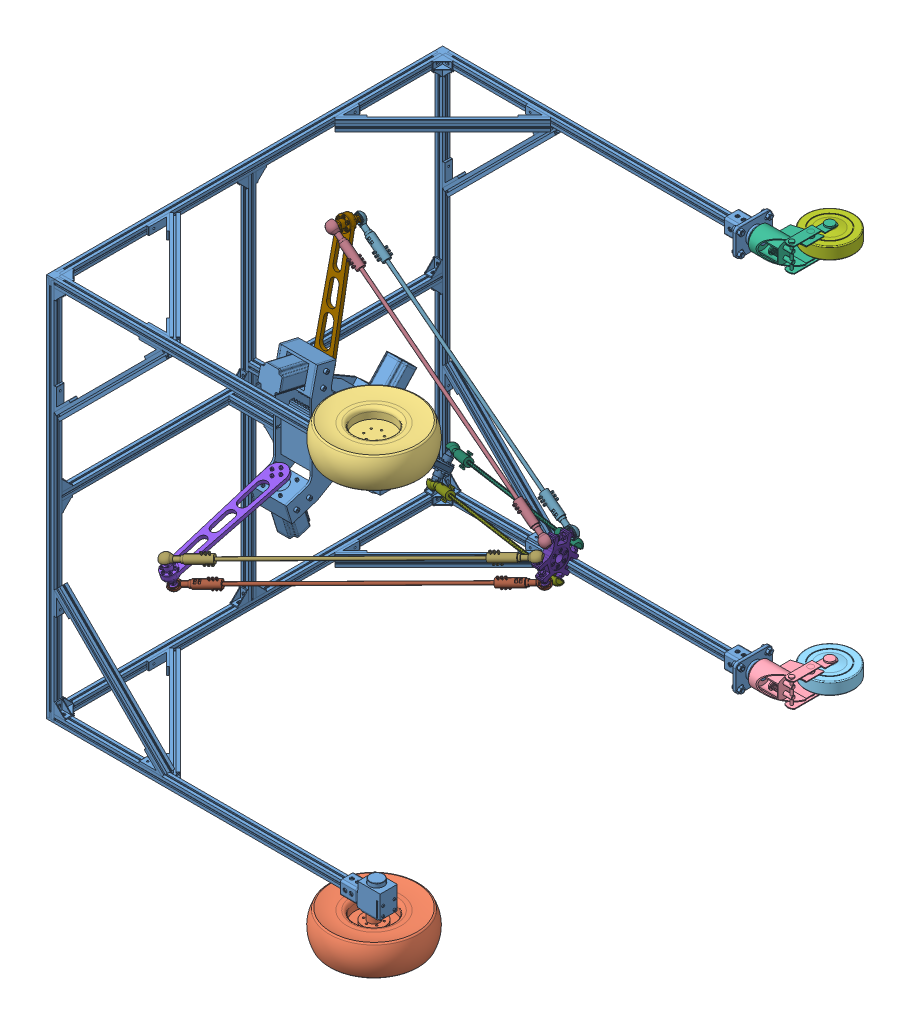
SolidWorks assembly ASM_copy, configuration Default. Lengths in mm.
Overall size (1014.86 1201.01 1337.44).
17 component instances, 17 part files, 27 mates.
Components (placement in the parent):
- Base-1: Base [默认] at (153.8383 -97.0811 -329.752) size (890.6 1072.4 1090.2)
- Driving_Wheel_1-1: Driving_Wheel_1 [默认] at (1013.8593 45.6114 1231.8039) x (1 0 0) z (0 1 0) size (257.62 257.62 86.31)
- Driving_Wheel_2-1: Driving_Wheel_2 [默认] at (1013.8593 1154.0114 1231.6593) x (1 0 0) z (0 -1 0) size (257.62 257.62 86.31)
- Link_Idler_Wheel_1-1: Link_Idler_Wheel_1 [默认] at (928.8665 41.2421 177.5322) x (0 -0.057419 0.99835) z (0 0.99835 0.057419) size (146.07 110.26 71.01)
- Idler_Wheel_1-1: Idler_Wheel_1 [默认] at (1090.3592 104.9114 111.5316) x (0 1 0) z (0.688622 0 -0.72512) size (40 125 125)
- Link_Idler_Wheel_2-1: Link_Idler_Wheel_2 [默认] at (928.8665 1031.2421 177.5322) x (0 -0.057419 0.99835) z (0 0.99835 0.057419) size (146.07 110.26 71.01)
- Idler_Wheel_2-1: Idler_Wheel_2 [默认] at (1090.3592 1094.9114 111.5316) x (0 -1 0) z (-0.118719 0 0.992928) size (40 125 125)
- Driving_Arm_1-1: Driving_Arm_1 [默认] at (491.5187 730.2809 769.1723) x (-0.999786 0.00612 -0.019764) z (-0.02069 -0.295741 0.955044) size (50 94.64 334)
- Driving_Arm_2-1: Driving_Arm_2 [默认] at (491.5187 586.7095 565.8859) x (-0.999786 -0.020176 0.004582) z (-0.02069 0.974963 -0.221403) size (50 94.64 334)
- Driving_Arm_3-1: Driving_Arm_3 [默认] at (491.5187 482.444 791.8655) x (-0.999786 0.014056 0.015182) z (-0.02069 -0.679222 -0.733641) size (50 94.64 334)
- Idler_Arm_1-1: Idler_Arm_1 [默认] at (625.108 556.338 323.4904) x (0.112964 0.846653 0.520017) z (0.510672 -0.498423 0.700563) size (34.32 751.8 29.42)
- Idler_Arm_2-1: Idler_Arm_2 [默认] at (1145.8798 654.078 1263.8018) x (-0.045285 -0.904508 -0.424046) z (-0.521051 0.383554 -0.762491) size (34.32 751.8 29.42)
- Idler_Arm_3-1: Idler_Arm_3 [默认] at (693.4424 1428.9939 737.0931) x (-0.131684 -0.36526 -0.921545) z (-0.506168 -0.774538 0.379322) size (34.32 751.8 29.42)
- Idler_Arm_4-1: Idler_Arm_4 [默认] at (170.3914 517.6998 469.2695) x (0.043969 0.228668 0.972511) z (0.521163 0.82525 -0.217605) size (34.32 751.8 29.42)
- Idler_Arm_5-1: Idler_Arm_5 [默认] at (625.3703 956.5035 862.6088) x (0.111171 -0.872414 0.475956) z (0.511065 -0.360557 -0.780264) size (34.32 751.8 29.42)
- Idler_Arm_6-1: Idler_Arm_6 [默认] at (1153.2971 113.313 445.7946) x (-0.084237 0.852323 -0.516188) z (-0.516187 0.405778 0.754252) size (34.32 751.8 29.42)
- End_Platform-1: End_Platform [默认] at (913.7087 579.5427 616.0715) x (0 -0.733799 0.679367) z (0 0.679367 0.733799) size (125.3 20 112.15)
Mates (geometry in assembly coordinates):
- 铰链1: hinge anti-aligned: cylinder of Base-1 through (1013.8593 63.6114 1231.8039) axis (0 1 0) radius 3; cylinder of Driving_Wheel_1-1 through (1013.8593 78.6114 1231.8039) axis (0 -1 0) radius 15; plane of Driving_Wheel_1-1 through (1013.8593 78.6114 1231.8039) normal (0 1 0); plane of Base-1 through (1013.8593 78.6114 1231.8039) normal (0 -1 0)
- 铰链3: hinge anti-aligned: cylinder of Base-1 through (1013.8593 1136.0114 1231.6593) axis (0 -1 0) radius 3; cylinder of Driving_Wheel_2-1 through (1013.8593 1121.0114 1231.6593) axis (0 1 0) radius 15; plane of Driving_Wheel_2-1 through (1013.8593 1121.0114 1231.6593) normal (0 -1 0); plane of Base-1 through (1013.8593 1121.0114 1231.6593) normal (0 1 0)
- 铰链4: hinge anti-aligned: cylinder of Link_Idler_Wheel_1-1 through (996.8592 104.9114 211.5316) axis (1 0 0) radius 20; cylinder of Base-1 through (1004.8592 104.9114 211.5316) axis (1 0 0) radius 7.5; plane of Base-1 through (1014.8592 114.5943 207.4705) normal (-1 0 0); plane of Link_Idler_Wheel_1-1 through (1014.8592 104.9114 211.5316) normal (1 0 0)
- 铰链5: hinge anti-aligned: cylinder of Idler_Wheel_1-1 through (1090.3592 84.9114 111.5316) axis (0 1 0) radius 8; cylinder of Link_Idler_Wheel_1-1 through (1090.3592 104.9114 111.5316) axis (0 1 0) radius 8; plane of Link_Idler_Wheel_1-1 through (1077.8592 84.9114 96.5316) normal (0 1 0); plane of Idler_Wheel_1-1 through (1090.3592 84.9114 111.5316) normal (0 -1 0)
- 铰链7: hinge anti-aligned: cylinder of Base-1 through (1004.8592 1094.9114 211.5316) axis (1 0 0) radius 7.5; cylinder of Link_Idler_Wheel_2-1 through (1006.8592 1094.9114 211.5316) axis (1 0 0) radius 30; plane of Base-1 through (1014.8592 1104.5943 207.4705) normal (-1 0 0); plane of Link_Idler_Wheel_2-1 through (1014.8592 1094.9114 211.5316) normal (1 0 0)
- 铰链8: hinge anti-aligned: cylinder of Link_Idler_Wheel_2-1 through (1090.3592 1094.9114 111.5316) axis (0 1 0) radius 8; cylinder of Idler_Wheel_2-1 through (1090.3592 1114.9114 111.5316) axis (0 -1 0) radius 8; plane of Link_Idler_Wheel_2-1 through (1102.8592 1114.9114 96.5316) normal (0 -1 0); plane of Idler_Wheel_2-1 through (1090.3592 1114.9114 111.5316) normal (0 1 0)
- 平行1: parallel aligned: plane of Base-1 through (1020.8592 1053.0114 1231.6316) normal (0 -1 0); plane of Link_Idler_Wheel_2-1 through (1077.8592 1062.9114 221.5316) normal (0 -1 0)
- 平行2: parallel aligned: plane of Base-1 through (1020.8592 146.6114 1231.8316) normal (0 1 0); plane of Link_Idler_Wheel_1-1 through (1102.8592 136.9114 221.5316) normal (0 1 0)
- 铰链9: hinge anti-aligned: cylinder of Driving_Arm_1-1 through (353.8592 520.8828 820.5229) axis (0 0.955249 0.295804) radius 4; cylinder of Base-1 through (353.8592 530.4353 823.4809) axis (0 -0.955249 -0.295804) radius 4; plane of Driving_Arm_1-1 through (353.8592 530.4353 823.4809) normal (0 -0.955249 -0.295804); plane of Base-1 through (353.8592 530.4353 823.4809) normal (0 0.955249 0.295804)
- 铰链10: hinge anti-aligned: cylinder of Base-1 through (353.8592 733.6649 711.8029) axis (0 0.22145 0.975172) radius 4; cylinder of Driving_Arm_2-1 through (353.8592 735.8794 721.5546) axis (0 -0.22145 -0.975172) radius 4; plane of Base-1 through (353.8592 733.6649 711.8029) normal (0 -0.22145 -0.975172); plane of Driving_Arm_2-1 through (353.8592 733.6649 711.8029) normal (0 0.22145 0.975172)
- 铰链11: hinge anti-aligned: cylinder of Base-1 through (353.8592 535.3341 591.6399) axis (0 0.733798 -0.679367) radius 4; cylinder of Driving_Arm_3-1 through (353.8592 542.6721 584.8462) axis (0 -0.733798 0.679367) radius 4; plane of Driving_Arm_3-1 through (353.8592 535.3341 591.6399) normal (0 0.733798 -0.679367); plane of Base-1 through (353.8592 535.3341 591.6399) normal (0 -0.733798 0.679367)
- 平行6: parallel aligned: plane of Base-1 through (303.8592 714.867 713.7929) normal (-1 0 0); plane of Driving_Arm_1-1 through (328.8592 533.301 824.3683) normal (-1 0 0)
- 平行7: parallel aligned: plane of Base-1 through (303.8592 714.867 713.7929) normal (-1 0 0); plane of Driving_Arm_2-1 through (328.8592 733.0006 708.8774) normal (-1 0 0)
- 平行8: parallel aligned: plane of Base-1 through (303.8592 714.867 713.7929) normal (-1 0 0); plane of Driving_Arm_3-1 through (328.8592 533.1327 593.678) normal (-1 0 0)
- 同心1: concentric: sphere of Driving_Arm_1-1; sphere of Idler_Arm_1-1
- 同心2: concentric: sphere of Driving_Arm_1-1; sphere of Idler_Arm_2-1
- 同心3: concentric: sphere of Driving_Arm_2-1; sphere of Idler_Arm_3-1
- 同心4: concentric: sphere of Driving_Arm_2-1; sphere of Idler_Arm_4-1
- 同心5: concentric: sphere of Driving_Arm_3-1; sphere of Idler_Arm_5-1
- 同心6: concentric: sphere of Driving_Arm_3-1; sphere of Idler_Arm_6-1
- 平行9: parallel anti-aligned: plane of Base-1 through (403.8592 713.4303 713.9368) normal (1 0 0); plane of End_Platform-1 through (958.1374 607.2103 669.3918) normal (-1 0 0)
- 同心7: concentric: sphere of Idler_Arm_1-1; sphere of End_Platform-1
- 同心8: concentric: sphere of Idler_Arm_2-1; sphere of End_Platform-1
- 同心9: concentric: sphere of Idler_Arm_3-1; sphere of End_Platform-1
- 同心10: concentric: sphere of Idler_Arm_4-1; sphere of End_Platform-1
- 同心11: concentric: sphere of Idler_Arm_5-1; sphere of End_Platform-1
- 同心12: concentric: sphere of Idler_Arm_6-1; sphere of End_Platform-1
